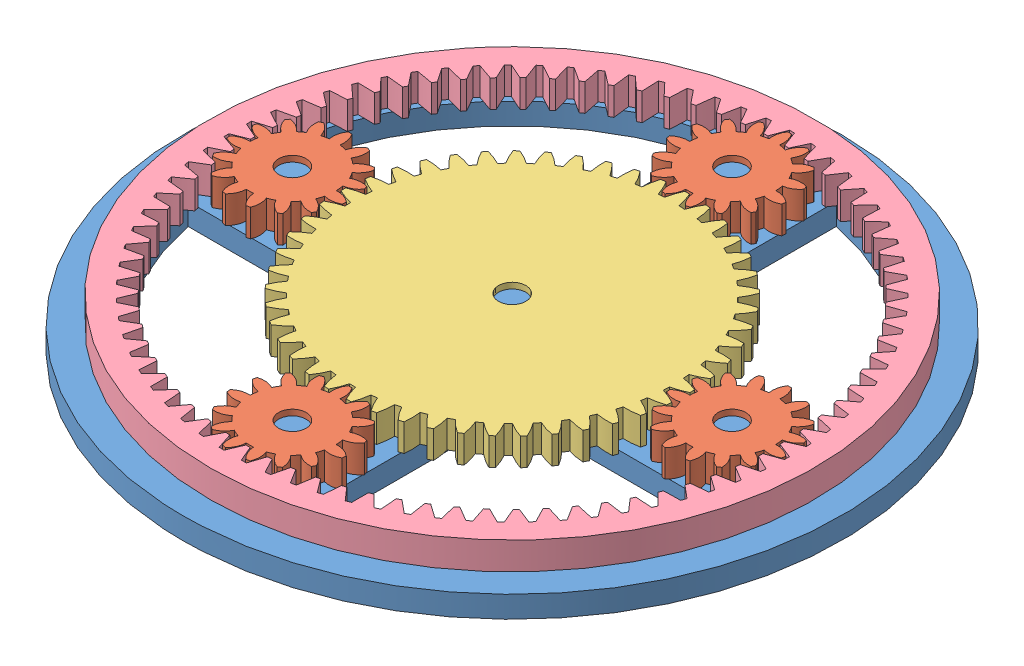
SolidWorks assembly Assem1, configuration Default. Lengths in mm.
Overall size (98.66 5.67 98.66).
7 component instances, 4 part files, 17 mates.
Components (placement in the parent):
- Pieza12.1-1: Pieza12.1 [Default] at (17.8944 35.6223 65.1728) size (76.2 5 76.2)
- Pieza12.2-1: Pieza12.2 [Default] at (17.8944 38.1223 39.7728) x (0.109263 0 0.994013) z (-0.994013 0 0.109263) size (13.37 3.17 13.3)
- Pieza12.2-2: Pieza12.2 [Default] at (-7.5056 38.1223 65.1728) x (-0.302956 0 0.953005) z (-0.953005 0 -0.302956) size (13.37 3.17 13.3)
- Pieza12.2-3: Pieza12.2 [Default] at (17.8944 38.1223 90.5728) x (0.978822 0 0.204712) z (-0.204712 0 0.978822) size (13.37 3.17 13.3)
- Pieza12.2-4: Pieza12.2 [Default] at (43.2944 38.1223 65.1728) x (0.502003 0 0.864866) z (-0.864866 0 0.502003) size (13.37 3.17 13.3)
- Pieza12.3-1: Pieza12.3 [Default] at (17.8944 38.1223 65.1728) x (-0.719101 0 0.694905) z (-0.694905 0 -0.719101) size (40.39 3.17 40.37)
- Pieza12.4-1: Pieza12.4 [Default] at (17.8944 38.1223 65.1728) x (-0.670351 0 0.742045) z (-0.742045 0 -0.670351) size (69.85 3.17 69.85)
Mates (geometry in assembly coordinates):
- Concentric1: concentric aligned: cylinder of Pieza12.1-1 through (17.8944 40.6223 65.1728) axis (0 -1 0) radius 1.5875; cylinder of Pieza12.3-1 through (17.8944 41.2973 65.1728) axis (0 -1 0) radius 1.5875
- Coincident1: coincident anti-aligned: plane of Pieza12.1-1 through (17.8944 38.1223 65.1728) normal (0 1 0); plane of Pieza12.3-1 through (26.4703 38.1223 68.363) normal (0 -1 0)
- Concentric2: concentric aligned: cylinder of Pieza12.1-1 through (-7.5056 40.6223 65.1728) axis (0 -1 0) radius 1.5875; cylinder of Pieza12.2-2 through (-7.5056 41.2973 65.1728) axis (0 -1 0) radius 1.5875
- Concentric3: concentric aligned: cylinder of Pieza12.1-1 through (17.8944 40.6223 90.5728) axis (0 -1 0) radius 1.5875; cylinder of Pieza12.2-3 through (17.8944 41.2973 90.5728) axis (0 -1 0) radius 1.5875
- Concentric4: concentric aligned: cylinder of Pieza12.1-1 through (43.2944 40.6223 65.1728) axis (0 -1 0) radius 1.5875; cylinder of Pieza12.2-4 through (43.2944 41.2973 65.1728) axis (0 -1 0) radius 1.5875
- Concentric5: concentric aligned: cylinder of Pieza12.1-1 through (17.8944 40.6223 39.7728) axis (0 -1 0) radius 1.5875; cylinder of Pieza12.2-1 through (17.8944 41.2973 39.7728) axis (0 -1 0) radius 1.5875
- Coincident3: coincident aligned: plane of Pieza12.2-2 through (-6.1286 38.1223 62.7348) normal (0 -1 0); plane of Pieza12.2-4 through (42.4148 38.1223 62.5146) normal (0 -1 0)
- Coincident4: coincident aligned: plane of Pieza12.2-3 through (15.3293 38.1223 89.4503) normal (0 -1 0); plane of Pieza12.2-4 through (42.4148 38.1223 62.5146) normal (0 -1 0)
- Coincident5: coincident aligned: plane of Pieza12.2-1 through (18.1652 38.1223 36.9859) normal (0 -1 0); plane of Pieza12.2-3 through (15.3293 38.1223 89.4503) normal (0 -1 0)
- Coincident6: coincident anti-aligned: plane of Pieza12.1-1 through (17.8944 38.1223 65.1728) normal (0 1 0); plane of Pieza12.2-2 through (-6.1286 38.1223 62.7348) normal (0 -1 0)
- Concentric7: concentric aligned: cylinder of Pieza12.1-1 through (17.8944 38.1223 65.1728) axis (0 -1 0) radius 38.1; cylinder of Pieza12.4-1 through (17.8944 41.2973 65.1728) axis (0 -1 0) radius 34.925
- Coincident7: coincident anti-aligned: plane of Pieza12.1-1 through (17.8944 38.1223 65.1728) normal (0 1 0); plane of Pieza12.4-1 through (17.8944 38.1223 65.1728) normal (0 -1 0)
- GearMate2: gear = 49 : 15 mm: circle of Pieza12.2-2; circle of Pieza12.3-1
- GearMate3: gear = 49 : 15 mm: circle of Pieza12.2-1; circle of Pieza12.3-1
- GearMate4: gear = 49 : 15 mm: circle of Pieza12.2-4; circle of Pieza12.3-1
- GearMate5: gear = 49 : 15 mm: circle of Pieza12.2-3; circle of Pieza12.3-1
- GearMate6: gear = 79 : 49 mm: circle of Pieza12.3-1; circle of Pieza12.4-1
